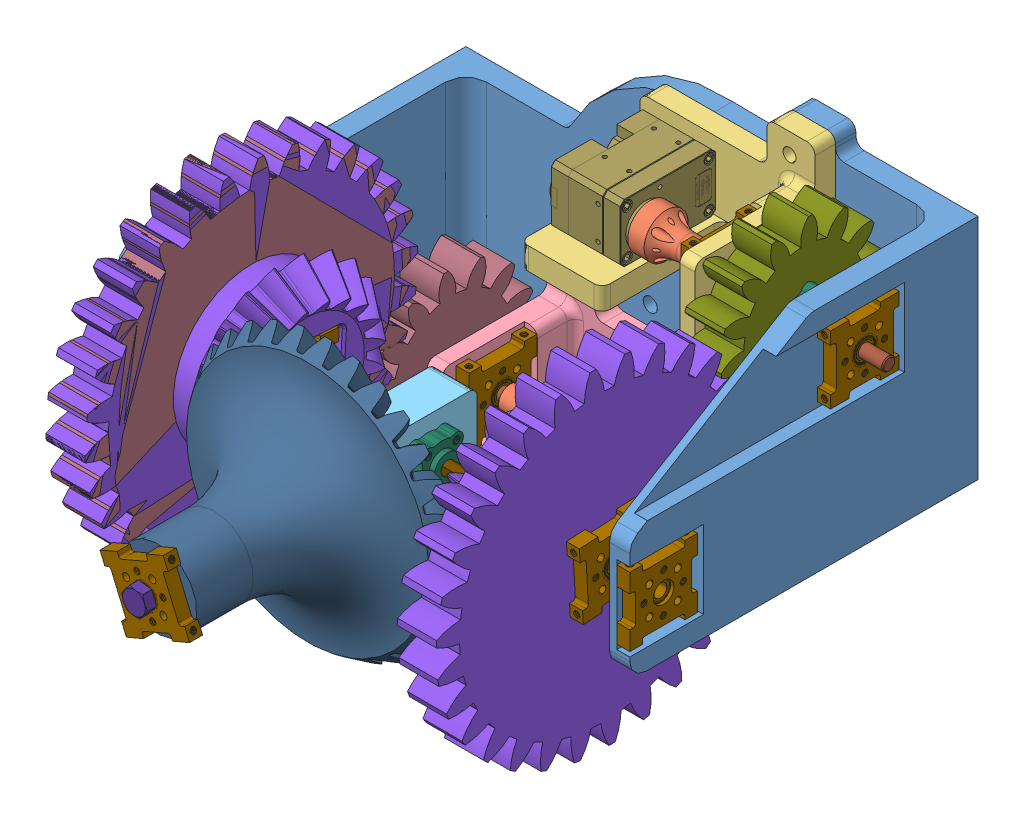
SolidWorks assembly ARMUS-REV2-000, configuration Défaut. Lengths in mm.
Overall size (273.8 250.65 287.77).
56 component instances, 21 part files, 70 mates.
Components (placement in the parent):
- ARMUS-REV2-001-1: ARMUS-REV2-001 [Default] at (100 950 50) x (1 0 0) z (0 -1 0) size (250 170 233.74)
- ARMUS-REV2-002-1: ARMUS-REV2-002 [Default] at (120 1003.2841 105.25) x (0 0.995713 0.092501) z (0 0.092501 -0.995713) size (22.05 28 22.05)
- ARMUS-REV2-004-1: ARMUS-REV2-004 [Défaut] at (96.91 942.0031 53.2662) x (1 0 0) z (0 -1 0) size (85.41 68.53 122.11)
- ARMUS-REV2-005-1: ARMUS-REV2-005 [Défaut] at (136.91 835.4348 53.2662) x (1 0 0) z (0 -1 0) size (85.41 68.53 122.11)
- ARMUS-REV2-200-1: ARMUS-REV2-200 [Défaut] at (100 967.5 203.49) x (0 0 1) z (1 0 0) size (54 35 20)
  - ARMUS-REV2-201-1: ARMUS-REV2-201 [Défaut] at origin size (54 35 20)
  - HUB-0_25-1: HUB-0_25 [Défaut] at (-30.0172 37.5992 -6.2696) x (-1 0 0) z (0 -1 0) size (25.4 12.7 25.4)
  - hex nut_ai-2: hex nut_ai [HNUT 0.2500-20-D-N] at (19.3798 17.5 0) x (0 0.5 0.866025) z (-1 0 0) size (11.11 12.83 5.74)
- ARMUS-REV2-300-1: ARMUS-REV2-300 [Default] at (176.2001 950 203.49) x (1 0 0) z (0 -0.998325 -0.057863) size (57.21 161.95 162.56)
  - ARMUS-REV2-301-1: ARMUS-REV2-301 [Default] at origin size (50.86 161.95 162.56)
  - Bore Side Tapped Pillow Block 1.25-1: Bore Side Tapped Pillow Block 1.25 [Default] at (-39.4159 7.6184 -28.3917) x (0 -1 0) z (0 0 1) size (33.54 6.35 33.02)
  - Bore Side Tapped Pillow Block 1.25-2: Bore Side Tapped Pillow Block 1.25 [Default] at (4.8346 7.6184 -28.3917) x (0 -1 0) z (0 0 1) size (33.54 6.35 33.02)
- ARMUS-REV2-400-1: ARMUS-REV2-400 [Défaut] at (100 950 252.232) x (0 0 -1) z (0.391177 -0.920315 0) size (99.55 130.43 130.79)
  - ARMUS-REV2-401-1: ARMUS-REV2-401 [Default] at origin size (93.2 130.43 130.79)
  - Bore Side Tapped Pillow Block 1.25-1: Bore Side Tapped Pillow Block 1.25 [Default] at (-58.9626 7.6184 28.3917) x (0 -1 0) z (0 0 -1) size (33.54 6.35 33.02)
  - Bore Side Tapped Pillow Block 1.25-2: Bore Side Tapped Pillow Block 1.25 [Default] at (26.0822 -28.3917 7.6184) x (0 0 -1) z (0 1 0) size (33.54 6.35 33.02)
- ARMUS-REV2-002-2: ARMUS-REV2-002 [Default] at (80 896.7159 105.25) x (0 -0.995713 0.092501) z (0 -0.092501 -0.995713) size (22.05 28 22.05)
- Bore Side Tapped Pillow Block 1.25-4: Bore Side Tapped Pillow Block 1.25 [Default] at (-4.4346 868.3241 112.8684) x (0 0 -1) z (0 1 0) size (33.54 6.35 33.02)
- D-Shaft 1.25x6-2: D-Shaft 1.25x6 [Default] at (13.9 896.7159 105.25) x (0 0.995713 -0.092501) z (1 0 0) size (6.35 5.71 101.6)
- Bore Side Tapped Pillow Block 1.25-5: Bore Side Tapped Pillow Block 1.25 [Default] at (-39.2154 957.6184 175.0983) x (0 -1 0) z (0 0 1) size (33.54 6.35 33.02)
- XM430-W350-R-3: XM430-W350-R [Default] at (99.4082 896.2291 93.9255) x (0 -1 0) z (-1 0 0) size (28.5 46.5 41)
- ARMUS-REV2-100-2: ARMUS-REV2-100 [Défaut] at (23.7999 950 203.49) x (-1 0 0) z (0 -0.449051 0.893506) size (50.86 161.95 162.56)
  - straight bevel pinion_ai-4: straight bevel pinion_ai [Inch - Straight bevel pinion 6DP20PT 30GT 20PA 0.75FW ---20O4H3MD0.5N] at (-9.9279 0 0) x (-1 0 0) z (0 0 -1) size (31.81 92.88 92.88) (hidden)
  - spur gear_ai-3: spur gear_ai [Inch - Spur gear 5DP 30T 20PA .75FW ---S30N3.0H2.0L0.5N] at origin size (19.05 161.95 162.56)
- spur gear_ai-19: spur gear_ai [Inch - Spur gear 5DP 14T 20PA 0.75FW ---S14N3.0H2.0L0.5N] at (23.7999 896.7159 105.25) x (-1 0 0) z (0 0.300831 -0.953677) size (19.05 79.69 81.28)
- ARMUS-REV2-300-2: ARMUS-REV2-300 [Default] at (23.7999 950 203.49) x (-1 0 0) z (0 0.998325 -0.057863) size (57.21 161.95 162.56)
  - ARMUS-REV2-301-1: ARMUS-REV2-301 [Default] at origin size (50.86 161.95 162.56)
  - Bore Side Tapped Pillow Block 1.25-1: Bore Side Tapped Pillow Block 1.25 [Default] at (-39.4159 7.6184 -28.3917) x (0 -1 0) z (0 0 1) size (33.54 6.35 33.02)
  - Bore Side Tapped Pillow Block 1.25-2: Bore Side Tapped Pillow Block 1.25 [Default] at (4.8346 7.6184 -28.3917) x (0 -1 0) z (0 0 1) size (33.54 6.35 33.02)
- hex screw_am-21: hex screw_am [B18.6.7M - M2 x 0.4 x 10 Indented HHMS --10N] at (106 904.7159 61.4) x (0 0 1) z (0.150087 0.988673 0) size (11.6 3.7 3.2)
- hex screw_am-22: hex screw_am [B18.6.7M - M2 x 0.4 x 10 Indented HHMS --10N] at (94 904.7159 61.4) x (0 0 1) z (0.304946 0.95237 0) size (11.6 3.7 3.2)
- hex screw_am-23: hex screw_am [B18.6.7M - M2 x 0.4 x 10 Indented HHMS --10N] at (106 888.7159 61.4) x (0 0 1) z (0.022976 0.999736 0) size (11.6 3.7 3.2)
- hex screw_am-24: hex screw_am [B18.6.7M - M2 x 0.4 x 10 Indented HHMS --10N] at (94 888.7159 61.4) x (0 0 1) z (-0.070312 0.997525 0) size (11.6 3.7 3.2)
- bore_set_screw_D_hub-2: bore_set_screw_D_hub [Défaut] at (130.7023 966.8226 256.0697) x (0 0 1) z (0 -1 0) size (20.57 9.61 20.57)
- ARMUS-REV2-500-1: ARMUS-REV2-500 [Défaut] at (195.2501 1003.2844 105.251) x (-1 0 0) z (0 0.558075 -0.829791) size (28.58 79.69 81.28)
  - ARMUS-REV2-501-1: ARMUS-REV2-501 [Défaut] at origin size (19.05 79.69 81.28)
  - bore_set_screw_D_hub-1: bore_set_screw_D_hub [Défaut] at (-20.7023 -52.5937 -16.7801) x (0 -1 0.000796) z (0 0.000796 1) size (20.57 9.61 20.57)
- z_env_0-1: z_env_0 [Default] at origin size (200 1000 50) (hidden)
- hex screw_am-11: hex screw_am [B18.6.7M - M2 x 0.4 x 10 Indented HHMS --10N] at (106 995.2841 61.4) x (0 0 1) z (-0.304946 -0.95237 0) size (11.6 3.7 3.2)
- hex screw_am-17: hex screw_am [B18.6.7M - M2 x 0.4 x 10 Indented HHMS --10N] at (94 995.2841 61.4) x (0 0 1) z (-0.150087 -0.988673 0) size (11.6 3.7 3.2)
- hex screw_am-18: hex screw_am [B18.6.7M - M2 x 0.4 x 10 Indented HHMS --10N] at (94 1011.2841 61.4) x (0 0 1) z (-0.022976 -0.999736 0) size (11.6 3.7 3.2)
- hex screw_am-19: hex screw_am [B18.6.7M - M2 x 0.4 x 10 Indented HHMS --10N] at (106 1011.2841 61.4) x (0 0 1) z (0.070312 -0.997525 0) size (11.6 3.7 3.2)
- hex bolt_ai-4: hex bolt_ai [HBOLT 0.2500-20x4.5x0.75-N] at (100 950 337.0652) x (0 0 -1) z (0.923728 0.383049 0) size (119.08 12.85 11.13)
- spur gear_ai-18: spur gear_ai [Inch - Spur gear 5DP 14T 20PA 0.75FW ---S14N3.0H2.0L0.5N] at (176.2001 1003.2841 105.25) x (1 0 0) z (0 -0.300831 -0.953677) size (19.05 79.69 81.28) (hidden)
- ARMUS-REV2-100-1: ARMUS-REV2-100 [Défaut] at (176.2001 950 203.49) x (1 0 0) z (0 0.449051 0.893506) size (50.86 161.95 162.56) (hidden)
  - straight bevel pinion_ai-4: straight bevel pinion_ai [Inch - Straight bevel pinion 6DP20PT 30GT 20PA 0.75FW ---20O4H3MD0.5N] at (-9.9279 0 0) x (-1 0 0) z (0 0 -1) size (31.81 92.88 92.88) (hidden)
  - spur gear_ai-3: spur gear_ai [Inch - Spur gear 5DP 30T 20PA .75FW ---S30N3.0H2.0L0.5N] at origin size (19.05 161.95 162.56)
- straight bevel gear_ai-7: straight bevel gear_ai [Inch - Straight bevel gear 6DP 30GT 20PT 20PA 0.75FW ---30O1.5H5.05MD0.5N] at (100 950 252.232) x (0 0 -1) z (0.683254 0.730181 0) size (99.55 130.43 130.79) (hidden)
- bore_set_screw_D_hub-1: bore_set_screw_D_hub [Défaut] at (69.2977 933.1774 256.0697) x (0 0 1) z (0 1 0) size (20.57 9.61 20.57)
- D-Shaft 1.25x8-1: D-Shaft 1.25x8 [Default] at (100 950 203.49) x (0 1 0) z (-1 0 0) size (6.35 5.71 203.2)
- D-Shaft 1.25x6-1: D-Shaft 1.25x6 [Default] at (186.1 1003.2841 105.25) x (0 -0.995713 -0.092501) z (-1 0 0) size (6.35 5.71 101.6)
- Bore Side Tapped Pillow Block 1.25-1: Bore Side Tapped Pillow Block 1.25 [Default] at (239.2154 942.3816 175.0983) x (0 1 0) z (0 0 1) size (33.54 6.35 33.02)
- Bore Side Tapped Pillow Block 1.25-3: Bore Side Tapped Pillow Block 1.25 [Default] at (204.4346 1031.6759 112.8684) x (0 0 -1) z (0 -1 0) size (33.54 6.35 33.02)
- XM430-W350-R-1: XM430-W350-R [Default] at (100.5918 1003.7709 93.9255) x (0 1 0) z (1 0 0) size (28.5 46.5 41)
- Bore Side Tapped Pillow Block 1.25-6: Bore Side Tapped Pillow Block 1.25 [Default] at (172.2154 995.6657 76.8583) x (0 1 0) z (0 0 1) size (33.54 6.35 33.02)
- Bore Side Tapped Pillow Block 1.25-7: Bore Side Tapped Pillow Block 1.25 [Default] at (27.7846 904.3343 76.8583) x (0 -1 0) z (0 0 1) size (33.54 6.35 33.02)
Mates (geometry in assembly coordinates):
- Coincident1: coordinate: point of z_env_0-1
- Concentric2: concentric aligned: cylinder of z_env_0-1 through (75 925 50) axis (0 0 1) radius 3.5; cylinder of ARMUS-REV2-001-1 through (75 925 60) axis (0 0 1) radius 3.5
- Concentric3: concentric aligned: cylinder of z_env_0-1 through (75 975 50) axis (0 0 1) radius 3.5; cylinder of ARMUS-REV2-001-1 through (75 975 60) axis (0 0 1) radius 3.5
- Coincident2: coincident anti-aligned: plane of z_env_0-1 through (0 0 50) normal (0 0 1); plane of ARMUS-REV2-001-1 through (100 950 50) normal (0 0 -1)
- Concentric4: concentric aligned: cylinder of ARMUS-REV2-001-1 through (225 956.9148 210.4048) axis (-1 0 0) radius 1.8986; cylinder of Bore Side Tapped Pillow Block 1.25-1 through (218.65 956.9148 210.4048) axis (-1 0 0) radius 1.778
- Concentric5: concentric aligned: cylinder of ARMUS-REV2-001-1 through (225 943.0852 196.5752) axis (-1 0 0) radius 1.8986; cylinder of Bore Side Tapped Pillow Block 1.25-1 through (218.65 943.0852 196.5752) axis (-1 0 0) radius 1.778
- Concentric6: concentric anti-aligned: cylinder of D-Shaft 1.25x8-1 through (201.6 950 203.49) axis (-1 0 0) radius 3.175; cylinder of Bore Side Tapped Pillow Block 1.25-1 through (218.6627 950 203.49) axis (1 0 0) radius 3.175
- Width1: width aligned: plane of D-Shaft 1.25x8-1 through (-1.6 950 203.49) normal (-1 0 0); plane of ARMUS-REV2-001-1 through (201.6 950 203.49) normal (1 0 0); plane of D-Shaft 1.25x8-1 through (-25 1091.6255 220) normal (-1 0 0); plane of ARMUS-REV2-001-1 through (225 1091.6255 220) normal (1 0 0)
- Coincident36: coincident anti-aligned: plane of ARMUS-REV2-001-1 through (218.65 930.95 183.975) normal (1 0 0); plane of Bore Side Tapped Pillow Block 1.25-1 through (218.65 950 203.49) normal (-1 0 0)
- Coincident37: coincident: plane of ARMUS-REV2-001-1 through (100 950 60) normal (0 0 1); plane of XM430-W350-R-1 through (117 1018.1944 70.361) normal (0 0 -1)
- Concentric33: concentric anti-aligned: cylinder of XM430-W350-R-1 through (122 1003.2841 105.25) axis (1 0 0) radius 4; cylinder of spur gear_ai-18 through (227.0002 1003.2841 105.25) axis (-1 0 0) radius 6.35
- Coincident38: coincident anti-aligned: plane of XM430-W350-R-1 through (120 1003.2841 105.25) normal (1 0 0); plane of ARMUS-REV2-002-1 through (120 1003.2841 105.25) normal (-1 0 0)
- Concentric37: concentric anti-aligned: cylinder of XM430-W350-R-1 through (120 1003.2841 105.25) axis (1 0 0) radius 9.75; cylinder of ARMUS-REV2-002-1 through (128 1003.2841 105.25) axis (-1 0 0) radius 10.75
- Concentric38: concentric anti-aligned: cylinder of ARMUS-REV2-002-1 through (119.999 1003.2841 105.25) axis (1 0 0) radius 3.375; cylinder of D-Shaft 1.25x6-1 through (236.9 1003.2841 105.25) axis (-1 0 0) radius 3.175
- Parallel6: parallel anti-aligned: plane of ARMUS-REV2-002-1 through (119.999 1001.6408 102.3455) normal (0 -0.092501 0.995713); plane of D-Shaft 1.25x6-1 through (236.9 1005.4159 102.8971) normal (0 0.092501 -0.995713)
- Distance2: distance = 12.7 mm anti-aligned: plane of D-Shaft 1.25x6-1 through (135.3 1003.2841 105.25) normal (-1 0 0); plane of ARMUS-REV2-002-1 through (148 1003.2841 105.25) normal (1 0 0)
- Concentric39: concentric aligned: cylinder of Bore Side Tapped Pillow Block 1.25-3 through (224.9873 1003.2841 105.25) axis (-1 0 0) radius 3.175; cylinder of D-Shaft 1.25x6-1 through (236.9 1003.2841 105.25) axis (-1 0 0) radius 3.175
- Parallel7: parallel anti-aligned: plane of ARMUS-REV2-001-1 through (100 950 60) normal (0 0 1); plane of Bore Side Tapped Pillow Block 1.25-3 through (225 986.7741 88.486) normal (0 0 -1)
- Parallel9: parallel anti-aligned: plane of ARMUS-REV2-001-1 through (100 950 60) normal (0 0 1); plane of XM430-W350-R-1 through (108.5 989.0341 70) normal (0 0 -1)
- Coincident44: coincident: plane of ARMUS-REV2-001-1 through (100 950 60) normal (0 0 1); plane of XM430-W350-R-1 through (108.5 995.2065 73.608) normal (0 0 -1)
- Coincident45: coincident anti-aligned: plane of ARMUS-REV2-001-1 through (218.65 950 50) normal (1 0 0); plane of Bore Side Tapped Pillow Block 1.25-3 through (218.65 1003.2841 105.25) normal (-1 0 0)
- Parallel10: parallel anti-aligned: plane of D-Shaft 1.25x8-1 through (201.6 948.095 206.03) normal (0 0 1); plane of Inch - Straight bevel gear 6DP 30GT 20PT 20PA 0.75FW ---30O1.5H2.5MD0.5N-5 through (100 950 240.0653) normal (0 0 -1)
- Width4: width: plane of ARMUS-REV2-001-1 through (0 1050 60) normal (0 1 0); plane of ARMUS-REV2-001-1 through (0 850 60) normal (0 -1 0); cylinder of Inch - Straight bevel gear 6DP 30GT 20PT 20PA 0.75FW ---30O1.5H2.5MD0.5N-5 through (87.3053 957.6268 299.9132) axis (0 0 -1) radius 19.05
- Coincident47: coincident anti-aligned: line of ARMUS-REV2-001-1 through (100 950 50) axis (0 0 1); line of straight bevel gear_ai-7 through (100 950 262.232) axis (0 0 -1)
- Concentric282: concentric anti-aligned: cylinder of D-Shaft 1.25x8-1 through (201.6 950 203.49) axis (-1 0 0) radius 3.175; cylinder of ARMUS-REV2-100-1/straight bevel pinion_ai-4 through (90.0722 950 203.49) axis (1 0 0) radius 6.35
- GearMate4: gear = 25.4 : 50.8 mm: cylinder of straight bevel gear_ai-7 through (100 950 331.7601) axis (0 0 -1) radius 19.05; cylinder of ARMUS-REV2-100-1/straight bevel pinion_ai-4 through (90.0722 950 203.49) axis (1 0 0) radius 6.35
- Coincident52: coincident: point of ARMUS-REV2-100-1/straight bevel pinion_ai-4; point of straight bevel gear_ai-7
- Concentric283: concentric aligned: cylinder of D-Shaft 1.25x8-1 through (201.6 950 203.49) axis (-1 0 0) radius 3.175; cylinder of ARMUS-REV2-100-1/spur gear_ai-3 through (227.0002 950 203.49) axis (-1 0 0) radius 6.35
- Width5: width aligned: plane of spur gear_ai-18 through (176.2001 1003.2841 105.25) normal (-1 0 0); plane of ARMUS-REV2-100-1/spur gear_ai-3 through (195.2501 1003.2841 105.25) normal (1 0 0); plane of spur gear_ai-18 through (176.2001 950 203.49) normal (-1 0 0); plane of ARMUS-REV2-100-1/spur gear_ai-3 through (195.2501 950 203.49) normal (1 0 0)
- Tangent4: tangent: circle of spur gear_ai-6; circle of ARMUS-REV2-100-1/spur gear_ai-2
- GearMate5: gear = 71.12 : 152.4 mm: circle of ARMUS-REV2-100-1/spur gear_ai-2; circle of spur gear_ai-6
- Width7: width aligned: plane of ARMUS-REV2-001-1 through (225 1091.6255 220) normal (1 0 0); plane of XM430-W350-R-1 through (-25 1091.6255 220) normal (-1 0 0); plane of ARMUS-REV2-001-1 through (117 1017.5341 70) normal (1 0 0); plane of XM430-W350-R-1 through (83 1017.5341 70) normal (-1 0 0)
- Coaxiale1: concentric anti-aligned: cylinder of D-Shaft 1.25x8-1 through (201.6 950 203.49) axis (-1 0 0) radius 3.175; cylinder of ARMUS-REV2-200-1/HUB-0_25-1 through (101.5875 950 203.49) axis (1 0 0) radius 3.175
- Coaxiale2: concentric aligned: cylinder of straight bevel gear_ai-7 through (100 950 123.962) axis (0 0 1) radius 6.35; cylinder of ARMUS-REV2-200-1/ARMUS-REV2-003-1 through (100 950 209.0097) axis (0 0 1) radius 3.175
- Parallèle1: parallel aligned: plane of D-Shaft 1.25x8-1 through (201.6 948.095 206.03) normal (0 0 1); plane of straight bevel gear_ai-7 through (100 950 252.232) normal (0 0 1)
- Coaxiale3: concentric aligned: cylinder of straight bevel gear_ai-7 through (100 950 123.962) axis (0 0 1) radius 6.35; cylinder of hex bolt_ai-4 through (100 950 337.0652) axis (0 0 1) radius 3.175
- Tangent6: tangent: circle of ARMUS-REV2-200-1/ARMUS-REV2-003-1; plane of hex bolt_ai-4 through (100 950 217.99) normal (0 0 -1)
- Coaxiale4: concentric aligned: cylinder of D-Shaft 1.25x6-1 through (236.9 1003.2841 105.25) axis (-1 0 0) radius 3.175; cylinder of ARMUS-REV2-004-1 through (198.411 1003.2841 105.25) axis (-1 0 0) radius 4.5
- Parallèle3: parallel anti-aligned: plane of ARMUS-REV2-001-1 through (100 950 60) normal (0 0 1); plane of ARMUS-REV2-004-1 through (100 950 60) normal (0 0 -1)
- Distance3: distance = 25 mm anti-aligned: plane of ARMUS-REV2-004-1 through (142 1022.1131 128.5266) normal (-1 0 0); plane of XM430-W350-R-1 through (117 1017.5341 70) normal (1 0 0)
- Coaxiale5: concentric anti-aligned: cylinder of D-Shaft 1.25x6-1 through (236.9 1003.2841 105.25) axis (-1 0 0) radius 3.175; cylinder of Bore Side Tapped Pillow Block 1.25-6 through (151.6627 1003.2841 105.25) axis (1 0 0) radius 3.175
- Coïncidente3: coincident anti-aligned: plane of ARMUS-REV2-004-1 through (158 984.0931 128.5266) normal (-1 0 0); plane of Bore Side Tapped Pillow Block 1.25-6 through (158 1003.2841 105.25) normal (1 0 0)
- Parallèle4: parallel aligned: plane of ARMUS-REV2-004-1 through (142 1022.1131 128.5266) normal (0 1 0); plane of Bore Side Tapped Pillow Block 1.25-6 through (151.65 1020.0481 94.836) normal (0 1 0)
- Coïncidente7: coincident anti-aligned: plane of XM430-W350-R-1 through (106 1011.2841 73) normal (0 0 -1); plane of hex screw_am-11 through (105.0476 995.5891 73) normal (0 0 1)
- Coaxiale15: concentric aligned: cylinder of D-Shaft 1.25x6-2 through (-36.9 896.7159 105.25) axis (1 0 0) radius 3.175; cylinder of ARMUS-REV2-005-1 through (1.589 896.7159 105.25) axis (1 0 0) radius 4.5
- Parallèle5: parallel anti-aligned: plane of ARMUS-REV2-001-1 through (100 950 60) normal (0 0 1); plane of ARMUS-REV2-005-1 through (100 843.4317 60) normal (0 0 -1)
- Coaxiale16: concentric anti-aligned: cylinder of D-Shaft 1.25x6-2 through (-36.9 896.7159 105.25) axis (1 0 0) radius 3.175; cylinder of Bore Side Tapped Pillow Block 1.25-7 through (48.3373 896.7159 105.25) axis (-1 0 0) radius 3.175
- Coaxiale17: concentric aligned: cylinder of ARMUS-REV2-005-1 through (34.59 903.6307 112.1648) axis (1 0 0) radius 1.778; cylinder of Bore Side Tapped Pillow Block 1.25-7 through (48.35 903.6307 112.1648) axis (1 0 0) radius 1.778
- Coïncidente14: coincident anti-aligned: plane of ARMUS-REV2-005-1 through (42 877.5248 128.5266) normal (1 0 0); plane of Bore Side Tapped Pillow Block 1.25-7 through (42 896.7159 105.25) normal (-1 0 0)
- Distance4: distance = 25 mm anti-aligned: plane of ARMUS-REV2-005-1 through (58 915.5448 128.5266) normal (1 0 0); plane of XM430-W350-R-3 through (83 882.4659 70) normal (-1 0 0)
- Concentric289: concentric aligned: cylinder of ARMUS-REV2-100-1/spur gear_ai-3 through (227.0002 950 203.49) axis (-1 0 0) radius 6.35; cylinder of ARMUS-REV2-300-1/Bore Side Tapped Pillow Block 1.25-2 through (201.5874 950 203.49) axis (-1 0 0) radius 3.175
- Concentric290: concentric aligned: cylinder of ARMUS-REV2-100-1/spur gear_ai-3 through (195.2501 881.6986 224.9874) axis (-1 0 0) radius 30.48; cylinder of ARMUS-REV2-300-1/ARMUS-REV2-301-1 through (195.2501 881.6986 224.9874) axis (-1 0 0) radius 30.48
- Coincident55: coincident aligned: plane of ARMUS-REV2-100-1/spur gear_ai-3 through (195.2501 950 203.49) normal (1 0 0); plane of ARMUS-REV2-300-1/ARMUS-REV2-301-1 through (195.2501 950 203.49) normal (1 0 0)
- Concentric298: concentric aligned: cylinder of ARMUS-REV2-400-1/ARMUS-REV2-401-1 through (100 950 123.962) axis (0 0 1) radius 6.35; cylinder of straight bevel gear_ai-7 through (100 950 123.962) axis (0 0 1) radius 6.35
- Coincident60: coincident aligned: plane of straight bevel gear_ai-7 through (100 950 240.0653) normal (0 0 -1); plane of ARMUS-REV2-400-1/ARMUS-REV2-401-1 through (100 950 240.0653) normal (0 0 -1)
- Concentric299: concentric anti-aligned: cylinder of hex bolt_ai-4 through (100 950 337.0652) axis (0 0 1) radius 3.175; cylinder of ARMUS-REV2-400-1/Bore Side Tapped Pillow Block 1.25-1 through (100 950 331.7474) axis (0 0 -1) radius 3.175
- Distance5: distance = 10 mm anti-aligned: plane of XM430-W350-R-1 through (108.5 989.0341 70) normal (0 0 -1); plane of ARMUS-REV2-001-1 through (100 950 60) normal (0 0 1)
- Concentric300: concentric anti-aligned: cylinder of ARMUS-REV2-004-1 through (106 995.2841 60) axis (0 0 1) radius 1; cylinder of hex screw_am-11 through (106 995.2841 36) axis (0 0 -1) radius 1
- Coincident61: coincident anti-aligned: plane of XM430-W350-R-1 through (106 1011.2841 73) normal (0 0 -1); plane of hex screw_am-17 through (93.0113 995.4342 73) normal (0 0 1)
- Concentric301: concentric anti-aligned: cylinder of ARMUS-REV2-004-1 through (94 995.2841 60) axis (0 0 1) radius 1; cylinder of hex screw_am-17 through (94 995.2841 36) axis (0 0 -1) radius 1
- Coincident62: coincident anti-aligned: plane of XM430-W350-R-1 through (106 1011.2841 73) normal (0 0 -1); plane of hex screw_am-18 through (93.0003 1011.3071 73) normal (0 0 1)
- Concentric302: concentric anti-aligned: cylinder of ARMUS-REV2-004-1 through (94 1011.2841 60) axis (0 0 1) radius 1; cylinder of hex screw_am-18 through (94 1011.2841 36) axis (0 0 -1) radius 1
- Coincident63: coincident anti-aligned: plane of XM430-W350-R-1 through (106 1011.2841 73) normal (0 0 -1); plane of hex screw_am-19 through (105.0025 1011.2138 73) normal (0 0 1)
- Concentric303: concentric anti-aligned: cylinder of ARMUS-REV2-004-1 through (106 1011.2841 60) axis (0 0 1) radius 1; cylinder of hex screw_am-19 through (106 1011.2841 36) axis (0 0 -1) radius 1
- Concentric304: concentric anti-aligned: cylinder of ARMUS-REV2-200-1/ARMUS-REV2-201-1 through (84.9711 956.9148 196.5752) axis (1 0 0) radius 1.778; cylinder of bore_set_screw_D_hub-1 through (90 956.9148 196.5752) axis (-1 0 0) radius 3.3722
- Concentric305: concentric anti-aligned: cylinder of ARMUS-REV2-200-1/ARMUS-REV2-201-1 through (84.9711 956.9148 210.4048) axis (1 0 0) radius 1.778; cylinder of bore_set_screw_D_hub-1 through (90 956.9148 210.4048) axis (-1 0 0) radius 3.3722
- Coincident65: coincident anti-aligned: plane of ARMUS-REV2-200-1/ARMUS-REV2-201-1 through (90 932.5 233.49) normal (-1 0 0); plane of bore_set_screw_D_hub-1 through (90 946.5426 200.0326) normal (1 0 0)
- Coincident66: coincident aligned: plane of spur gear_ai-18 through (176.2001 1003.2841 105.25) normal (-1 0 0); plane of ARMUS-REV2-500-1/ARMUS-REV2-501-1 through (176.2001 1003.2844 105.251) normal (-1 0 0)
- Concentric306: concentric aligned: cylinder of D-Shaft 1.25x6-1 through (236.9 1003.2841 105.25) axis (-1 0 0) radius 3.175; cylinder of ARMUS-REV2-500-1/bore_set_screw_D_hub-1 through (195.2501 1003.2842 105.25) axis (-1 0 0) radius 3.175
- Coincident67: coincident anti-aligned: circle of spur gear_ai-18; circle of ARMUS-REV2-500-1/ARMUS-REV2-501-1
